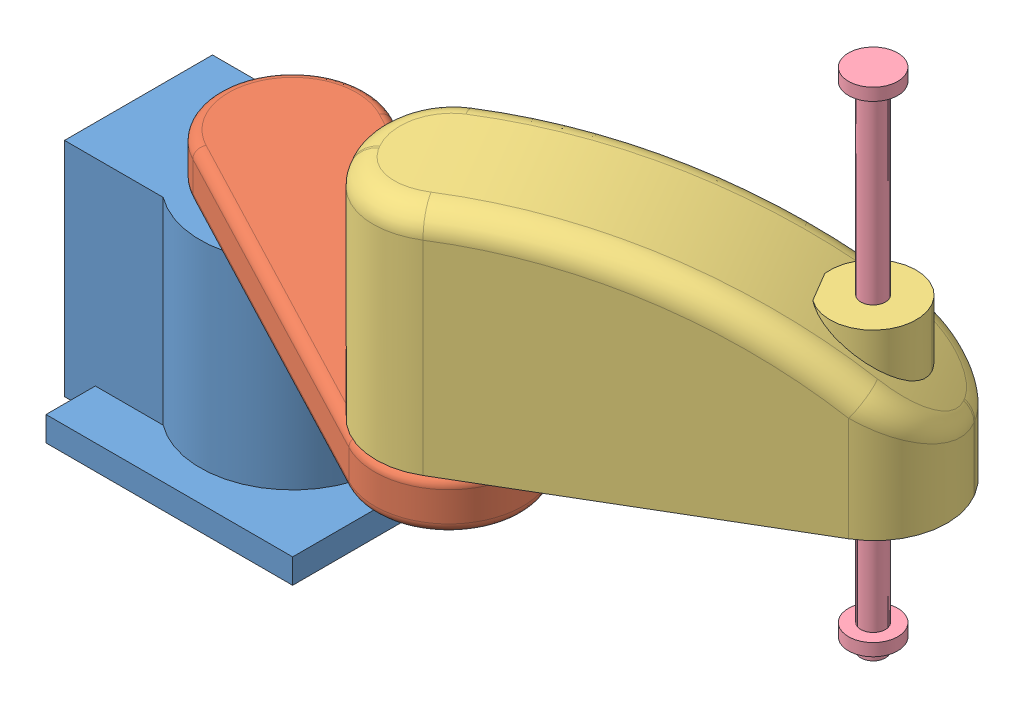
SolidWorks assembly scara, configuration Default. Lengths in mm.
Overall size (688.6 510 320.13).
4 component instances, 4 part files, 6 mates.
Components (placement in the parent):
- lk0-Body-1: lk0-Body [Default] x (1 0 0) z (0 1 0) size (225 200 180)
- lk1-Body-1: lk1-Body [Default] at (0 220 0) x (0.885928 0 0.463823) z (0 -1 0) size (420 120 40)
- lk2-Body-1: lk2-Body [Default] at (266.1313 220 137.7774) x (0.861193 0 -0.508279) z (0 1 0) size (370 120 205.33)
- lk3-Body-1: lk3-Body [Default] at (481.4294 120 10.7077) x (0.999423 0 0.033955) z (0 -1 0) size (40 40 410)
Mates (geometry in assembly coordinates):
- Coincident1: coincident anti-aligned: plane of lk0-Body-1 through (-37.6499 180 0) normal (0 1 0); plane of lk1-Body-1 through (132.8892 180 69.5734) normal (0 -1 0)
- Concentric1: concentric aligned: circle of lk0-Body-1; cylinder of lk1-Body-1 through (0 220 0) axis (0 1 0) radius 60
- Coincident2: coincident anti-aligned: plane of lk1-Body-1 through (132.8892 220 69.5734) normal (0 1 0); plane of lk2-Body-1 through (183.963 220 116.6026) normal (0 -1 0)
- Concentric3: concentric aligned: cylinder of lk1-Body-1 through (265.7784 220 139.1469) axis (0 1 0) radius 60; cylinder of lk2-Body-1 through (265.7784 220 139.1469) axis (0 1 0) radius 59
- Concentric4: concentric anti-aligned: cylinder of lk2-Body-1 through (481.4294 200 10.7077) axis (0 1 0) radius 10; cylinder of lk3-Body-1 through (481.4294 500 10.7077) axis (0 -1 0) radius 10
- Distance1: distance = 150 mm anti-aligned: plane of lk3-Body-1 through (481.4294 500 10.7077) normal (0 -1 0); plane of lk2-Body-1 through (481.4294 350 10.7077) normal (0 1 0)
